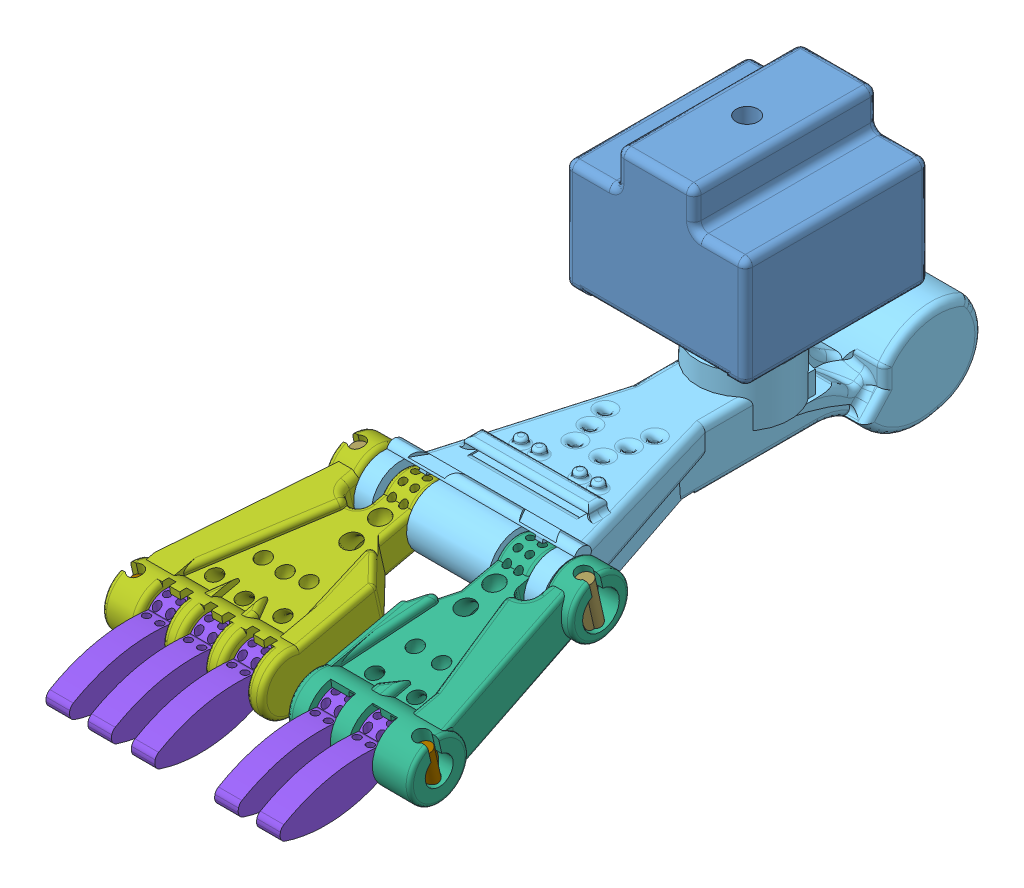
SolidWorks assembly Foot Ankle, configuration Fully Constrained. Lengths in mm.
Overall size (106.69 107.23 259.88).
22 component instances, 15 part files, 64 mates.
Components (placement in the parent):
- Ankle Exterior-1: Ankle Exterior [Default] at (-20.5538 13.3388 22.6611)
- Ankle Middle Joint Shell-1: Ankle Middle Joint Shell [Default] at (30.5162 13.8468 51.8711) x (-1 0 0) z (0 0 1)
- Ankle Interior Joint-1: Ankle Interior Joint [Default] at (30.7702 13.8468 51.8711) x (-1 0 0) z (0 0 1)
- Ankle Bottom Joint-1: Ankle Bottom Joint [Default] at (10.3232 11.3068 37.5281)
- New foot - Copy - Copy-1: New foot - Copy - Copy [Default] at (24.928 10.5643 16.707) x (0 0 1) z (-1 0 0)
- Left mid foot-1: Left mid foot [Default] at (43.58 -18.2815 210.0017) x (-1 0 0) z (0 0.219565 -0.975598)
- New Front foot-1: New Front foot [Default] at (-21.7787 -23.2375 208.8863) x (1 0 0) z (0 0.219565 -0.975598)
- Toe-1: Toe [Default] at (-5.0147 -29.4326 207.4921) x (1 0 0) z (0 -0.152333 0.988329)
- Toe-2: Toe [Default] at (23.768 -29.4326 207.4921) x (1 0 0) z (0 -0.152333 0.988329)
- Toe-3: Toe [Default] at (-20.0007 -29.4326 207.4921) x (1 0 0) z (0 -0.152333 0.988329)
- Toe-4: Toe [Default] at (-34.4787 -29.4326 207.4921) x (1 0 0) z (0 -0.152333 0.988329)
- Toe-5: Toe [Default] at (38.246 -29.4326 207.4921) x (1 0 0) z (0 -0.152333 0.988329)
- small axle lock-1: small axle lock [Default] at (-42.8607 -35.6276 206.0978) x (0 -0.219565 0.975598) z (-1 0 0)
- small axle-1: small axle [Default] at (6.1613 -29.4326 207.4921) x (0 0.929388 0.369105) z (0 -0.369105 0.929388)
- foot axle-1: foot axle [Default] at (4.3833 -15.4902 145.5416) x (0 -0.687163 -0.726504) z (0 0.726504 -0.687163)
- large axle lock-1: large axle lock [Default] at (-27.9844 -24.1633 143.5897) x (1 0 0) z (0 -0.219565 0.975598)
- small axle - Copy-2: small axle - Copy [Default] at (49.676 -29.4326 207.4921) x (0 0.989317 0.145783) z (0 -0.145783 0.989317)
- foot axle-2: foot axle [Default] at (17.418 -15.4902 145.5416) x (0 0.421139 -0.906996) z (0 -0.906996 -0.421139)
- large axle lock-2: large axle lock [Default] at (49.93 -24.4341 143.3876) x (0.965851 0.056889 -0.252776) z (0.259098 -0.212067 0.942282)
- small axle lock-2: small axle lock [Default] at (56.026 -36.1419 205.9821) x (0.478376 -0.192812 0.856726) z (-0.878155 -0.105034 0.466702)
- Ankle Lock 1-1: Ankle Lock 1 [Default] at (9.6964 11.3068 50.4741) x (0 0 1) z (-1 0 0)
- Foot T Lock-1: Foot T Lock [Default] at (10.8874 -8.2512 49.2121) x (1 0 0) z (0 1 0)
Mates (geometry in assembly coordinates):
- Concentric1: concentric aligned: circle of Ankle Middle Joint Shell-1; circle of Ankle Interior Joint-1
- Coincident1: coincident aligned: plane of Ankle Middle Joint Shell-1 through (30.5162 13.8468 51.8711) normal (1 0 0); plane of Ankle Interior Joint-1 through (30.5162 13.8468 51.8711) normal (1 0 0)
- Coincident2: coincident anti-aligned: plane of Ankle Middle Joint Shell-1 through (30.5162 13.8468 51.8711) normal (0 -1 0); plane of Ankle Interior Joint-1 through (30.7702 13.8468 51.8711) normal (0 1 0)
- Distance1: distance = 1 mm anti-aligned: plane of Ankle Interior Joint-1 through (30.5162 13.8468 51.8711) normal (1 0 0); plane of Ankle Exterior-1 through (31.5162 16.3868 26.4711) normal (-1 0 0)
- LimitAngle1: limit planar angle = 0.349066 rad aligned: plane of Ankle Middle Joint Shell-1 through (30.5162 13.8468 51.8711) normal (0 -1 0); plane of Ankle Exterior-1 through (-20.5538 23.8372 24.4227) normal (0 -0.939693 -0.34202)
- Concentric4: concentric aligned: circle of Ankle Exterior-1; circle of Ankle Middle Joint Shell-1
- Concentric5: concentric anti-aligned: circle of Ankle Interior Joint-1; circle of Ankle Bottom Joint-1
- Distance2: distance = 0.5 mm anti-aligned: plane of Ankle Bottom Joint-1 through (10.3232 11.3068 67.8811) normal (0 0 1); plane of Ankle Interior Joint-1 through (-3.0118 11.3068 68.3811) normal (0 0 -1)
- LimitAngle2: limit planar angle = 0 rad anti-aligned: plane of Ankle Interior Joint-1 through (30.7702 11.3068 51.8711) normal (0 -1 0); plane of Ankle Bottom Joint-1 through (-3.0977 3.8138 37.5281) normal (-0.488212 0.872725 0)
- Coincident6: coincident: plane of Ankle Bottom Joint-1 through (23.9684 11.3068 48.3866) normal (0 0 -1); line of New foot - Copy - Copy-1 through (21.9014 -0.2502 48.3866) axis (-1 0 0)
- Parallel1: parallel anti-aligned: plane of Ankle Bottom Joint-1 through (10.3232 0.2578 37.5281) normal (0 -1 0); plane of New foot - Copy - Copy-1 through (10.958 -0.2502 53.4666) normal (0 1 0)
- Concentric9: concentric aligned: circle of New Front foot-1; circle of Toe-1
- Coincident10: coincident anti-aligned: plane of New Front foot-1 through (3.1133 -23.2375 208.8863) normal (-1 0 0); plane of Toe-1 through (3.1133 -29.4326 207.4921) normal (1 0 0)
- Concentric10: concentric aligned: circle of New Front foot-1; circle of Toe-3
- Coincident11: coincident anti-aligned: circle of New Front foot-1; plane of Toe-3 through (-20.0007 -29.4326 207.4921) normal (-1 0 0)
- Concentric11: concentric aligned: circle of New Front foot-1; circle of Toe-4
- Coincident12: coincident anti-aligned: circle of New Front foot-1; plane of Toe-4 through (-34.4787 -29.4326 207.4921) normal (-1 0 0)
- Concentric12: concentric aligned: circle of Left mid foot-1; circle of Toe-2
- Coincident13: coincident aligned: circle of Left mid foot-1; plane of Toe-2 through (23.768 -29.4326 207.4921) normal (-1 0 0)
- Concentric13: concentric aligned: circle of Left mid foot-1; circle of Toe-5
- Coincident14: coincident anti-aligned: circle of Left mid foot-1; plane of Toe-5 through (38.246 -29.4326 207.4921) normal (-1 0 0)
- Concentric14: concentric anti-aligned: cylinder of New Front foot-1 through (-41.5907 -15.4902 145.5416) axis (1 0 0) radius 6.35; circle of foot axle-1
- Concentric15: concentric anti-aligned: circle of New Front foot-1; cylinder of small axle-1 through (-39.3047 -29.4326 207.4921) axis (1 0 0) radius 4.3815
- Concentric16: concentric aligned: circle of Left mid foot-1; circle of small axle-2
- Concentric18: concentric aligned: circle of Left mid foot-1; circle of foot axle-2
- Coincident20: coincident: plane of New Front foot-1 through (6.1613 -29.4326 207.4921) normal (-1 0 0); line of small axle-1 through (6.1613 -25.177 206.4492) axis (0 -0.369105 0.929388)
- Concentric20: concentric anti-aligned: cylinder of New Front foot-1 through (-42.8607 -25.7156 208.3286) axis (0 0.975598 0.219565) radius 2.54; cylinder of small axle lock-1 through (-42.8607 -23.2375 208.8863) axis (0 -0.975598 -0.219565) radius 2.413
- Concentric21: concentric aligned: cylinder of New Front foot-1 through (22.3513 -29.4326 207.4921) axis (-1 0 0) radius 4.826; cylinder of small axle lock-1 through (-41.5907 -29.4326 207.4921) axis (-1 0 0) radius 4.191
- Concentric24: concentric aligned: circle of New Front foot-1; circle of large axle lock-1
- Coincident23: coincident: line of New Front foot-1 through (-29.8088 -9.928 148.6049) axis (0 0.975598 0.219565); cylinder of large axle lock-1 through (-27.9844 -6.8172 147.4935) axis (0 -0.975598 -0.219565) radius 2.54
- Concentric25: concentric anti-aligned: circle of New foot - Copy - Copy-1; cylinder of foot axle-2 through (46.628 -15.4902 145.5416) axis (-1 0 0) radius 6.1595
- Concentric26: concentric anti-aligned: circle of New foot - Copy - Copy-1; cylinder of foot axle-1 through (-24.8267 -15.4902 145.5416) axis (1 0 0) radius 6.1595
- Coincident24: coincident aligned: plane of New foot - Copy - Copy-1 through (17.418 -15.4902 145.5416) normal (1 0 0); circle of foot axle-2
- Coincident25: coincident aligned: plane of New foot - Copy - Copy-1 through (4.3833 10.5643 16.707) normal (-1 0 0); circle of foot axle-1
- Concentric28: concentric anti-aligned: circle of Left mid foot-1; cylinder of foot axle-2 through (46.628 -15.4902 145.5416) axis (-1 0 0) radius 6.1595
- Coincident26: coincident anti-aligned: circle of New foot - Copy - Copy-1; plane of Left mid foot-1 through (25.038 -35.6276 206.0978) normal (-1 0 0)
- Concentric29: concentric aligned: circle of New Front foot-1; cylinder of foot axle-1 through (-24.8267 -15.4902 145.5416) axis (1 0 0) radius 6.1595
- Coincident27: coincident anti-aligned: plane of New foot - Copy - Copy-1 through (-3.2367 10.5643 16.707) normal (-1 0 0); plane of New Front foot-1 through (-3.2367 -35.6276 206.0978) normal (1 0 0)
- Concentric31: concentric anti-aligned: circle of Ankle Bottom Joint-1; cylinder of New foot - Copy - Copy-1 through (10.8874 -8.2512 28.0666) axis (0 0 1) radius 2.032
- Coincident30: coincident anti-aligned: plane of Left mid foot-1 through (19.196 -29.4326 207.4921) normal (1 0 0); circle of small axle - Copy-2
- Parallel3: parallel aligned: plane of Ankle Exterior-1 through (-20.5538 13.3388 83.6211) normal (0 0 1); plane of Ankle Interior Joint-1 through (30.7702 13.8468 78.9221) normal (0 0 1)
- Parallel6: parallel aligned: plane of Ankle Interior Joint-1 through (30.7702 11.3068 51.8711) normal (0 -1 0); plane of Ankle Bottom Joint-1 through (10.3232 0.2578 37.5281) normal (0 -1 0)
- Concentric32: concentric anti-aligned: cylinder of Left mid foot-1 through (49.93 -54.3649 136.6515) axis (0 0.975598 0.219565) radius 2.54; cylinder of large axle lock-2 through (49.93 -7.0879 147.2914) axis (0 -0.975598 -0.219565) radius 2.54
- Coincident31: coincident: cylinder of Left mid foot-1 through (63.392 -15.4902 145.5416) axis (-1 0 0) radius 6.35; point of large axle lock-2
- Concentric33: concentric anti-aligned: cylinder of Left mid foot-1 through (56.026 -68.3375 198.7363) axis (0 0.975598 0.219565) radius 2.54; cylinder of small axle lock-2 through (56.026 -23.7518 208.7706) axis (0 -0.975598 -0.219565) radius 2.413
- Coincident33: coincident: cylinder of Left mid foot-1 through (4.53 -29.4326 207.4921) axis (1 0 0) radius 4.826; point of small axle lock-2
- Lock1: lock: unknown of Left mid foot-1; unknown of large axle lock-2
- Lock2: lock: unknown of Left mid foot-1; unknown of small axle lock-2
- Concentric34: concentric aligned: circle of Ankle Interior Joint-1; cylinder of Ankle Lock 1-1 through (24.4202 26.0388 51.9981) axis (0 -1 0) radius 1.016
- Parallel8: parallel anti-aligned: plane of Ankle Interior Joint-1 through (25.6902 24.0068 64.4441) normal (-1 0 0); plane of Ankle Lock 1-1 through (25.4362 24.0068 40.5681) normal (1 0 0)
- Coincident34: coincident: plane of Ankle Interior Joint-1 through (30.7702 24.0068 51.8711) normal (0 -1 0); line of Ankle Lock 1-1 through (23.4042 24.0068 40.5681) axis (0 0 1)
- Concentric35: concentric anti-aligned: cylinder of New foot - Copy - Copy-1 through (10.8874 -8.2512 28.0666) axis (0 0 1) radius 2.032; circle of Foot T Lock-1
- Coincident35: coincident anti-aligned: plane of Ankle Bottom Joint-1 through (10.8874 -8.2512 49.2121) normal (0 0 -1); plane of Foot T Lock-1 through (10.8874 -8.2512 49.2121) normal (0 0 1)
- Parallel9: parallel aligned: plane of Ankle Exterior-1 through (34.0562 13.3388 81.0811) normal (0 -1 0); plane of Ankle Middle Joint Shell-1 through (30.5162 13.8468 51.8711) normal (0 -1 0)
- Parallel10: parallel aligned: plane of Ankle Exterior-1 through (34.0562 13.3388 81.0811) normal (0 -1 0); plane of Ankle Bottom Joint-1 through (10.3232 0.2578 37.5281) normal (0 -1 0)
- Tangent2: tangent aligned: cylinder of Toe-5 through (-0.7259 5.0922 233.2476) axis (1 0 0) radius 44.6847
- Tangent3: tangent aligned: cylinder of Toe-2 through (-15.2039 5.0922 233.2476) axis (1 0 0) radius 44.6847
- Tangent5: tangent aligned: cylinder of Left mid foot-1 through (59.836 -29.4326 207.4921) axis (-1 0 0) radius 10.16
- Tangent6: tangent aligned: cylinder of New Front foot-1 through (-46.6707 -29.4326 207.4921) axis (1 0 0) radius 10.16
- Tangent7: tangent aligned: cylinder of Toe-5 through (-0.7259 5.0922 233.2476) axis (1 0 0) radius 44.6847
- Tangent8: tangent aligned: cylinder of Toe-2 through (-15.2039 5.0922 233.2476) axis (1 0 0) radius 44.6847
- Tangent9: tangent aligned: cylinder of Toe-1 through (-43.9866 5.0922 233.2476) axis (1 0 0) radius 44.6847
- Tangent10: tangent aligned: cylinder of Toe-3 through (-58.9726 5.0922 233.2476) axis (1 0 0) radius 44.6847
- Tangent11: tangent aligned: cylinder of Toe-4 through (-73.4506 5.0922 233.2476) axis (1 0 0) radius 44.6847
